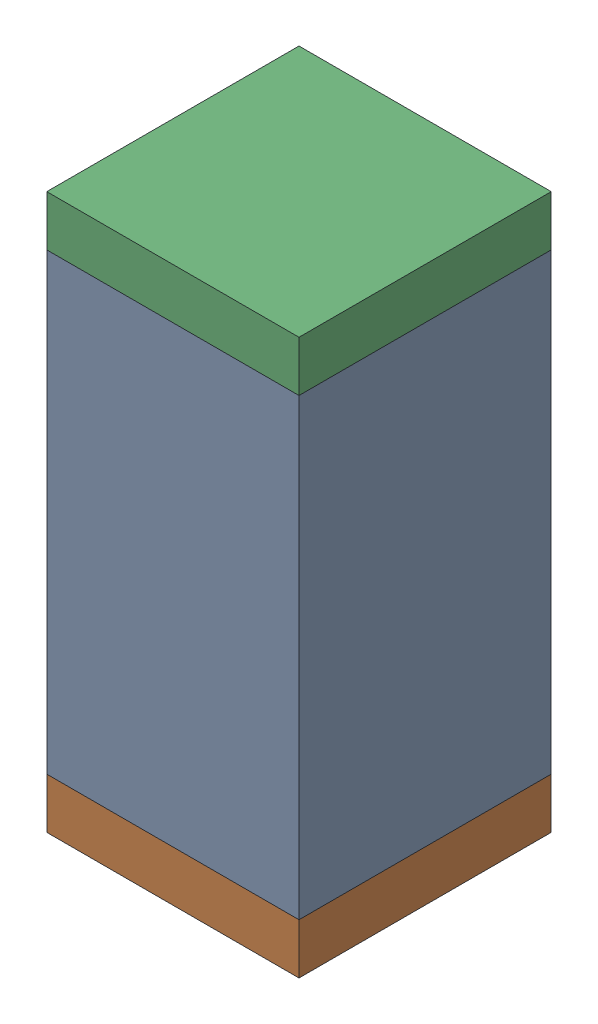
SolidWorks assembly C105, configuration Default. Lengths in mm.
Overall size (0.5 1.1 0.5).
6 component instances, 2 part files, 0 mates.
Components (placement in the parent):
- 791586336-1: 791586336 [Default] at (120.45 72.45 0) size (0.5 0.9 0.5)
  - Extruded_8-1: Extruded_8 [Default] at origin size (0.5 0.9 0.5)
- 810157360-1: 810157360 [Default] at (120.45 71.95 0) size (0.5 0.1 0.5)
  - Extruded_9-1: Extruded_9 [Default] at origin size (0.5 0.1 0.5)
- 810157360-2: 810157360 [Default] at (120.45 72.95 0) size (0.5 0.1 0.5)
  - Extruded_9-1: Extruded_9 [Default] at origin size (0.5 0.1 0.5)
